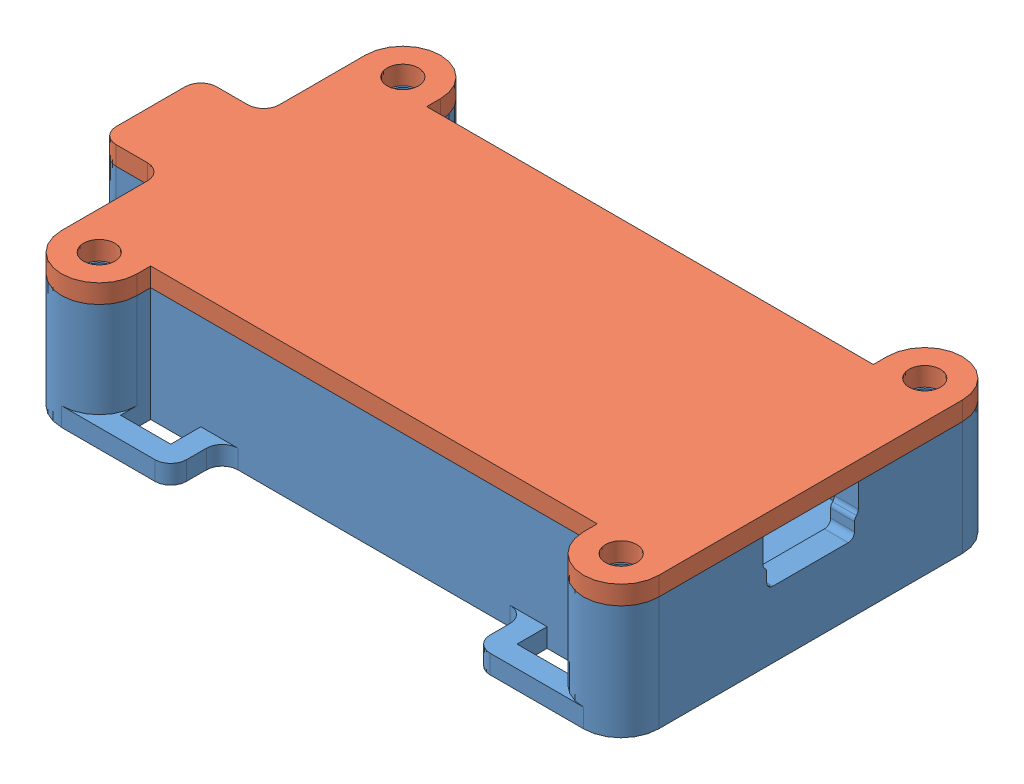
SolidWorks assembly arduino-case, configuration Default. Lengths in mm.
Overall size (52.6 10.6 30.2).
2 component instances, 2 part files, 4 mates.
Components (placement in the parent):
- arduino-case-bottom-1: arduino-case-bottom [Default] at origin size (52.6 9.1 30.2)
- arduino-case-top-1: arduino-case-top [Default] at (0 7.6 0) x (1 0 0) z (0 1 0) size (52.6 30.2 1.5)
Mates (geometry in assembly coordinates):
- InPlace1: in place: plane of arduino-case-bottom-1 through (0 7.6 0) normal (0 1 0); plane of arduino-case-top-1 through (0 7.6 0) normal (0 1 0); moOrthogonalPlaneRef_w of arduino-case-bottom-1 through (0 7.6 0) normal (0 1 0); plane of arduino-case-top-1 through (0 7.6 0) normal (0 0 -1); plane of arduino-case-bottom-1 through (0 7.6 0) normal (0 1 0); plane of arduino-case-top-1 through (0 7.6 0) normal (1 0 0); plane of arduino-case-bottom-1 through (0 7.6 0) normal (0 1 0); unknown of arduino-case-top-1
- Coincident1: coincident: plane of arduino-case-bottom-1; plane of arduino-case-top-1
- Coincident2: coincident: moOrthogonalPlaneRef_w of arduino-case-bottom-1 through (0 7.6 0) normal (0 0 -1); plane of arduino-case-top-1 through (0 7.6 0) normal (0 0 -1)
- Coincident3: coincident: moOrthogonalPlaneRef_w of arduino-case-bottom-1 through (0 7.6 0) normal (-1 0 0); plane of arduino-case-top-1 through (0 7.6 0) normal (1 0 0)
